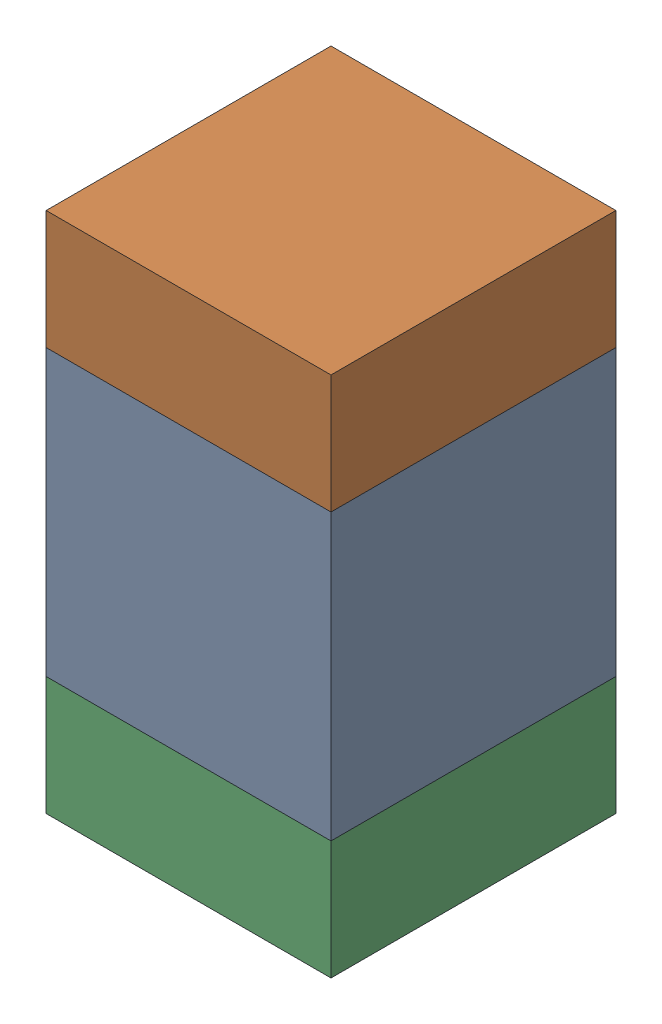
SolidWorks assembly C120_2PCB, configuration Default. Lengths in mm.
Overall size (0.6 1.1 0.6).
6 component instances, 2 part files, 0 mates.
Components (placement in the parent):
- 761606048-1: 761606048 [Default] at (114.2 98 0) size (0.6 0.6 0.6)
  - Extruded_9-1: Extruded_9 [Default] at origin size (0.6 0.6 0.6)
- 854785296-1: 854785296 [Default] at (114.2 98.425 0) size (0.6 0.25 0.6)
  - Extruded_10-1: Extruded_10 [Default] at origin size (0.6 0.25 0.6)
- 854785296-2: 854785296 [Default] at (114.2 97.575 0) size (0.6 0.25 0.6)
  - Extruded_10-1: Extruded_10 [Default] at origin size (0.6 0.25 0.6)
